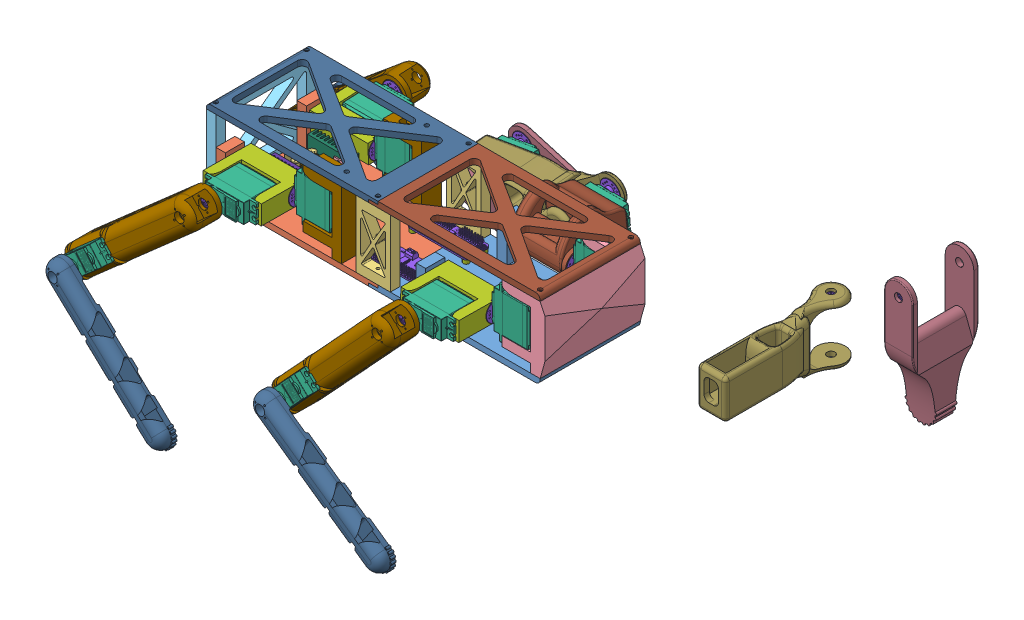
SolidWorks assembly RoboDogV3, configuration Standard. Lengths in mm.
Overall size (554.11 248.86 448.17).
97 component instances, 32 part files, 139 mates.
Components (placement in the parent):
- BottomPlate_Front-1: BottomPlate_Front [Standard] at (70.3304 -10.5488 180) size (180 46 105)
- BottomPlate_Back-1: BottomPlate_Back [Standard] at (-94.2849 -10.5488 185.4725) size (180 46 105)
- StructurePlate_MiddlePart-1: StructurePlate_MiddlePart [Standard] at (-22.5267 -4.5488 248) size (36 70 10)
- StructurePlate_MiddlePart-2: StructurePlate_MiddlePart [Standard] at (-22.5267 -4.5488 153) size (36 70 10)
- StructurePlate_Front-1: StructurePlate_Front [Standard] at (147.4733 -4.5488 258) x (0 0 -1) z (1 0 0) size (105.12 70 52.16)
- StructurePlate_Back-1: StructurePlate_Back [Standard] at (-182.5267 -4.5488 153) x (0 0 1) z (-1 0 0) size (105 70 10)
- mg996r-1: mg996r [Default] at (117.4733 34.4012 248.15) x (0 -1 0) z (0 0 -1) size (56.95 44.55 19.7)
- mg996r-2: mg996r [Default] at (117.4733 34.4012 162.85) x (0 -1 0) z (0 0 -1) size (56.95 44.55 19.7)
- ServoPart_ShoulderRight-1: ServoPart_ShoulderRight [Standard] at (40.4233 34.1896 237.0496) x (1 0 0) z (0 -0.999949 0.010096) size (73 50.02 20.04)
- mg996r-3: mg996r [Default] at (71.4733 24.8449 287.1465) x (-1 0 0) z (0 0.999949 -0.010096) size (56.95 44.55 19.7)
- attachmentCircular (1)-1: attachmentCircular (1) [Default] at (99.4233 24.3012 248.15) x (0 -1 0) z (0 0 1) size (20.7 5.75 20.7)
- Teil1^RoboDogV3-1: Teil1^RoboDogV3 [Standard] at origin (virtual)
- StructurePart_BackLegs-1: StructurePart_BackLegs [Standard] at (-50.9186 -4.5488 237) x (0 0 1) z (-1 0 0) size (21.05 70 40.02)
- mg996r-5: mg996r [Default] at (-90.9186 35.5012 246.85) x (0 -1 0) z (0 0 -1) size (56.95 44.55 19.7)
- mg996r-6: mg996r [Default] at (-136.9186 25.8546 285.8477) x (-1 0 0) z (0 0.99997 -0.00778) size (56.95 44.55 19.7)
- attachmentCircular (1)-3: attachmentCircular (1) [Default] at (-108.9686 25.4012 246.85) x (0 -1 0) z (0 0 1) size (20.7 5.75 20.7)
- ServoPart_ShoulderRight-3: ServoPart_ShoulderRight [Standard] at (-167.9686 35.3153 235.7725) x (1 0 0) z (0 -0.99997 0.00778) size (73 50.02 20.04)
- ServoPart_ShoulderRight-4: ServoPart_ShoulderRight [Standard] at (-167.9686 14.9087 173.3812) x (1 0 0) z (0 0.998954 0.045725) size (73 50.02 20.04)
- attachmentCircular (1)-4: attachmentCircular (1) [Default] at (-108.9686 25.4012 162.85) x (0 -1 0) z (0 0 1) size (20.7 5.75 20.7)
- mg996r-7: mg996r [Default] at (-136.9186 27.0346 123.8839) x (-1 0 0) z (0 -0.998954 -0.045725) size (56.95 44.55 19.7)
- mg996r-8: mg996r [Default] at (-90.9186 35.5012 162.85) x (0 -1 0) z (0 0 -1) size (56.95 44.55 19.7)
- StructurePart_BackLegs-2: StructurePart_BackLegs [Standard] at (-50.9186 -4.5488 153) x (0 0 1) z (-1 0 0) size (21.05 70 40.02)
- TopPlate_Back-1: TopPlate_Back [Standard] at (-105.3838 71.4512 180) x (-1 0 0) z (0 0 1) size (180 6 105)
- TopPlate_Front-1: TopPlate_Front [Standard] at (59.2315 71.4512 185.4725) x (-1 0 0) z (0 0 1) size (180 6 105)
- dcdc_converter.STEP-1: dcdc_converter.STEP [Standard] at (-133.5601 1.0512 205.6181) x (0.008727 0 -0.999962) z (0.999962 0 0.008727) size (53.6 27.7 60)
  - Bornera_terminal_7_62mm_2P.STEP-1: Bornera_terminal_7_62mm_2P.STEP [Standard] at (-0.13 0 17.5) x (-1 0 0) z (0 0 -1) size (16.14 14.75 12.1)
    - terminal-Base.STEP-1: terminal-Base.STEP [Standard] at origin size (16.14 12.5 12.1)
    - screw pad.STEP-1: screw pad.STEP [Standard] at (-3.8725 6.75 -5.95) size (6 9.75 10)
    - screw-term.STEP-1: screw-term.STEP [Standard] at (-3.8725 7.5 -5.95) x (-0.497999 0 -0.867177) z (0.867177 0 -0.497999) size (5 6.51 5)
    - screw pad.STEP-2: screw pad.STEP [Standard] at (3.8725 6.75 -5.95) size (6 9.75 10)
    - screw-term.STEP-2: screw-term.STEP [Standard] at (3.8725 7.5 -5.95) x (-0.426017 0 -0.904715) z (0.904715 0 -0.426017) size (5 6.51 5)
  - Bornera_terminal_7_62mm_2P.STEP-2: Bornera_terminal_7_62mm_2P.STEP [Standard] at (-7.13 0 -29.4) x (-1 0 0) z (0 0 -1) size (16.14 14.75 12.1)
    - terminal-Base.STEP-1: terminal-Base.STEP [Standard] at origin size (16.14 12.5 12.1)
    - screw pad.STEP-1: screw pad.STEP [Standard] at (-3.8725 6.75 -5.95) size (6 9.75 10)
    - screw-term.STEP-1: screw-term.STEP [Standard] at (-3.8725 7.5 -5.95) x (-0.497999 0 -0.867177) z (0.867177 0 -0.497999) size (5 6.51 5)
    - screw pad.STEP-2: screw pad.STEP [Standard] at (3.8725 6.75 -5.95) size (6 9.75 10)
    - screw-term.STEP-2: screw-term.STEP [Standard] at (3.8725 7.5 -5.95) x (-0.426017 0 -0.904715) z (0.904715 0 -0.426017) size (5 6.51 5)
  - heatsink 45x10x12r.STEP-1: heatsink 45x10x12r.STEP [Standard] at (16.8 0 0) size (10 25 45)
  - pcb.STEP-1: pcb.STEP [Standard] at origin size (45.5 1.61 60)
  - heatsink 45x10x12r-0.STEP-1: heatsink 45x10x12r-0.STEP [Standard] at (-16.8 0 0) x (-1 0 0) z (0 0 -1) size (10 25 45)
  - coil.STEP-1: coil.STEP [Standard] at (0 12.5 1) size (24 24 11)
  - Trimpot 3296W_Valor predeterminado.STEP-1: Trimpot 3296W_Valor predeterminado.STEP [Standard] at (9.485 0 -27.085) x (-1 0 0) z (0 1 0) size (9.53 4.83 14.15)
  - Trimpot 3296W_Valor predeterminado.STEP-2: Trimpot 3296W_Valor predeterminado.STEP [Standard] at (9.485 0 -21.755) x (-1 0 0) z (0 1 0) size (9.53 4.83 14.15)
  - c20x10x5.STEP-1: c20x10x5.STEP [Standard] at (5.27 0.525 11.8) x (0 0 -1) z (1 0 0) size (10.05 23.25 16.46)
  - c20x10x5.STEP-2: c20x10x5.STEP [Standard] at (-5.27 0.525 11.8) x (0 0 -1) z (1 0 0) size (10.05 23.25 16.46)
  - c20x8x4.STEP-1: c20x8x4.STEP [Standard] at (0 0.525 -9) x (0 0 -1) z (1 0 0) size (8.05 23.25 13.09)
  - c20x8x4.STEP-2: c20x8x4.STEP [Standard] at (-8.1 0.525 -9) x (0 0 -1) z (1 0 0) size (8.05 23.25 13.09)
  - c20x8x4.STEP-3: c20x8x4.STEP [Standard] at (8.1 0.525 -9) x (0 0 -1) z (1 0 0) size (8.05 23.25 13.09)
  - MOSFET.STEP-1: MOSFET.STEP [Standard] at (-16.8 9.3003 11.65) x (0 0 -1) z (1 0 0) size (10.16 22.6 4.45)
  - MOSFET.STEP-2: MOSFET.STEP [Standard] at (16.8 9.3003 11.65) x (0 0 1) z (-1 0 0) size (10.16 22.6 4.45)
  - 3mm LED.STEP-1: 3mm LED.STEP [Standard] at (-12.05 5 22.2) x (-1 0 0) z (0 0 -1) size (3.4 10.4 3.8)
  - Selector Switch - SS12D00.STEP-1: Selector Switch - SS12D00.STEP [Standard] at (14.1989 2.1071 23.2) x (0 0 -1) z (1 0 0) size (8.59 9.5 3.71)
- DistancingRing-1: DistancingRing [Standard] at (-105.3067 -0.5488 218.5) x (-0.837169 0 -0.546944) z (-0.546944 0 0.837169) size (6 4 6)
- DistancingRing-2: DistancingRing [Standard] at (-105.3021 -0.5488 192.5) x (-0.837169 0 -0.546944) z (-0.546944 0 0.837169) size (6 4 6)
- DistancingRing-3: DistancingRing [Standard] at (-163.3021 -4.5488 192.5) size (6 4 6)
- DistancingRing-4: DistancingRing [Standard] at (-163.3067 -0.5488 218.5) x (-0.837169 0 -0.546944) z (-0.546944 0 0.837169) size (6 4 6)
- DistancingRing-5: DistancingRing [Standard] at (116.3693 -0.5488 229.0306) x (-0.837169 0 -0.546944) z (-0.546944 0 0.837169) size (6 4 6)
- DistancingRing-6: DistancingRing [Standard] at (116.3693 -0.5488 180.0306) x (-0.837169 0 -0.546944) z (-0.546944 0 0.837169) size (6 4 6)
- DistancingRing-7: DistancingRing [Standard] at (58.3693 -0.5488 180.0306) x (-0.837169 0 -0.546944) z (-0.546944 0 0.837169) size (6 4 6)
- DistancingRing-8: DistancingRing [Standard] at (58.3693 -0.5488 229.0306) x (-0.837169 0 -0.546944) z (-0.546944 0 0.837169) size (6 4 6)
- 12Channel PWM-1: 12Channel PWM [Default] at (-15.1746 -0.5488 181.423) x (0.00022 0 1) z (-1 0 0.00022) size (25.4 7.55 66.7)
- 12Channel PWM-2: 12Channel PWM [Default] at (-15.1726 -0.5488 229.57) x (0 0 -1) z (1 0 0) size (25.4 7.55 66.7)
- DistancingRing-9: DistancingRing [Standard] at (-43.1267 -4.5488 172.0292) size (6 4 6)
- DistancingRing-10: DistancingRing [Standard] at (-43.1226 -4.5488 190.8284) size (6 4 6)
- DistancingRing-11: DistancingRing [Standard] at (-43.1226 -4.5488 238.97) size (6 4 6)
- DistancingRing-12: DistancingRing [Standard] at (-43.1226 -4.5488 220.17) size (6 4 6)
- DistancingRing-13: DistancingRing [Standard] at (12.7774 -4.5488 190.8169) size (6 4 6)
- DistancingRing-14: DistancingRing [Standard] at (12.7733 -4.5488 172.0169) size (6 4 6)
- DistancingRing-15: DistancingRing [Standard] at (12.7774 -4.5488 238.97) size (6 4 6)
- DistancingRing-16: DistancingRing [Standard] at (12.7774 -4.5488 220.17) size (6 4 6)
- Leg_UpperPart-1: Leg_UpperPart [Standard] at (-273.3611 -65.0539 302.6054) x (-0.751239 -0.66001 0.005135) z (-0.66003 0.751217 -0.005844) size (170 30.18 30.18)
- attachmentCircular (1)-5: attachmentCircular (1) [Default] at (-147.0186 25.995 303.8971) x (0.751239 0.66001 -0.005135) z (-0.66003 0.751217 -0.005844) size (20.7 5.75 20.7)
- attachmentCircular (1)-6: attachmentCircular (1) [Default] at (61.3733 25.0271 305.1956) x (0.677926 0.735093 -0.007422) z (-0.73513 0.677891 -0.006844) size (20.7 5.75 20.7)
- Leg_UpperPart-2: Leg_UpperPart [Standard] at (-54.7322 -78.764 304.2434) x (-0.677926 -0.735093 0.007422) z (-0.73513 0.677891 -0.006844) size (170 30.18 30.18)
- attachmentCircular (1)-8: attachmentCircular (1) [Default] at (-147.0186 27.86 105.8528) x (0.766628 0.64142 0.02936) z (0.642092 -0.765826 -0.035054) size (20.7 5.75 20.7)
- Leg_UpperPart-4: Leg_UpperPart [Standard] at (-256.2145 -83.139 102.7741) x (-0.766628 -0.64142 -0.02936) z (0.642092 -0.765826 -0.035054) size (170 30.18 30.18)
- mg996r-9: mg996r [Default] at (-22.3983 -66.0422 334.1165) x (-0.677926 -0.735093 0.007422) z (-0.73513 0.677891 -0.006844) size (56.95 44.55 19.7)
- mg996r-10: mg996r [Default] at (-240.73 -56.5843 332.5404) x (-0.751239 -0.66001 0.005135) z (-0.66003 0.751217 -0.005844) size (56.95 44.55 19.7)
- mg996r-11: mg996r [Default] at (-243.6238 -50.1886 74.251) x (-0.766628 -0.64142 -0.02936) z (0.642092 -0.765826 -0.035054) size (56.95 44.55 19.7)
- Leg Bottom-1: Leg Bottom [Standard] at (-237.8462 -89.7658 348.849) x (0.735504 -0.6775 0.005271) z (0 0.00778 0.99997) size (166.25 27.5 15)
- attachmentCircular (1)-9: attachmentCircular (1) [Default] at (-248.3176 -63.11 350.6417) x (0.735504 -0.6775 0.005271) z (0.677521 0.735481 -0.005722) size (20.7 5.75 20.7)
- attachmentCircular (1)-10: attachmentCircular (1) [Default] at (-29.2454 -73.2844 352.2405) x (0.822234 -0.569121 0.005746) z (0.56915 0.822192 -0.008301) size (20.7 5.75 20.7)
- Leg Bottom-2: Leg Bottom [Standard] at (-15.186 -98.2377 350.4923) x (0.822234 -0.569121 0.005746) z (0 0.010096 0.999949) size (166.25 27.5 15)
- attachmentCircular (1)-12: attachmentCircular (1) [Default] at (-251.3668 -55.8416 55.9233) x (0.787176 -0.616083 -0.0282) z (-0.616728 -0.786353 -0.035994) size (20.7 5.75 20.7)
- Leg Bottom-4: Leg Bottom [Standard] at (-223.3866 -61.9687 57.645) x (0.787176 -0.616083 -0.0282) z (0 0.045725 -0.998954) size (166.25 27.5 15)
- attachmentCircular (1)-13: attachmentCircular (1) [Default] at (98.4233 24.3012 162.85) x (0 -0.080731 0.996736) z (0 0.996736 0.080731) size (20.7 5.75 20.7)
- Shoulder-1: Shoulder [Standard] at (37.9233 24.3012 162.85) x (0 0.089032 -0.996029) z (1 0 0) size (78.66 54.3 75)
- mg996r-13: mg996r [Default] at (68.8733 29.0925 104.545) x (-1 0 0) z (0 -0.996029 -0.089032) size (56.95 44.55 19.7)
- mg996r-14: mg996r [Default] at (-38.5219 12.4325 88.498) x (-0.983751 -0.178826 -0.015985) z (0.179539 -0.979844 -0.087585) size (56.95 44.55 19.7)
- LegTop-1: LegTop [Standard] at (30.1585 15.8904 136.4965) x (0 -0.089032 0.996029) z (-0.983751 -0.178826 -0.015985) size (63.28 30 140.57)
- attachmentCircular (1)-14: attachmentCircular (1) [Default] at (58.7733 30.9621 83.6284) x (0.698629 -0.712642 -0.063701) z (-0.715484 -0.695855 -0.0622) size (20.7 5.75 20.7)
- LegBottom-1: LegBottom [Standard] at (74.9502 -12.136 63.2102) x (-0.313233 -0.945905 -0.084551) z (0 0.089032 -0.996029) size (33 141.27 69)
- attachmentCircular (1)-15: attachmentCircular (1) [Default] at (-48.4578 12.407 68.416) x (0.903765 0.426329 0.038108) z (0.428029 -0.900176 -0.080464) size (20.7 5.75 20.7)
- LegBottom-2: LegBottom [Standard] at (247.1201 -139.1368 -12.9277) size (33 141.27 69)
- LegTop-3: LegTop [Standard] at (154.911 -132.4306 -14.4716) x (0 -1 0) z (0 0 1) size (63.28 30 140.57)
- attachmentCircular (1)-16: attachmentCircular (1) [Default] at (262.1201 -14.1368 -15.9277) x (-0.923728 -0.383049 0) z (0.383049 -0.923728 0) size (20.7 5.75 20.7)
- attachmentCircular (1)-17: attachmentCircular (1) [Default] at (159.911 -78.4306 -44.4716) x (-0.837169 0 -0.546944) z (-0.546944 0 0.837169) size (20.7 5.75 20.7)
Mates (geometry in assembly coordinates):
- Deckungsgleich1: coincident anti-aligned: line of BottomPlate_Front-1 through (-22.5267 -7.5488 153) axis (0 0 1); line of BottomPlate_Back-1 through (-22.5267 -7.5488 258) axis (0 0 -1)
- Deckungsgleich2: coincident anti-aligned: line of BottomPlate_Front-1 through (-22.5267 -7.5488 258) axis (1 0 0); line of BottomPlate_Back-1 through (-12.5267 -7.5488 258) axis (-1 0 0)
- Konzentrisch1: concentric aligned: circle of BottomPlate_Back-1; circle of StructurePlate_MiddlePart-1
- Deckungsgleich3: coincident aligned: line of BottomPlate_Back-1 through (-192.5267 -4.5488 258) axis (1 0 0); line of StructurePlate_MiddlePart-1 through (-35.6225 -4.5488 258) axis (1 0 0)
- Konzentrisch2: concentric aligned: circle of BottomPlate_Back-1; circle of StructurePlate_MiddlePart-2
- Deckungsgleich4: coincident anti-aligned: line of BottomPlate_Back-1 through (-12.5267 -4.5488 153) axis (-1 0 0); line of StructurePlate_MiddlePart-2 through (-35.6225 -4.5488 153) axis (1 0 0)
- Deckungsgleich5: coincident aligned: line of BottomPlate_Front-1 through (157.4733 -4.5488 258) axis (0 0 -1); line of StructurePlate_Front-1 through (157.4733 -4.5488 258) axis (0 0 -1)
- Konzentrisch5: concentric anti-aligned: circle of BottomPlate_Back-1; circle of StructurePlate_Back-1
- Konzentrisch6: concentric anti-aligned: circle of BottomPlate_Back-1; circle of StructurePlate_Back-1
- Deckungsgleich6: coincident aligned: line of BottomPlate_Back-1 through (-192.5267 -4.5488 153) axis (0 0 1); line of StructurePlate_Back-1 through (-192.5267 -4.5488 153) axis (0 0 1)
- Konzentrisch8: concentric anti-aligned: circle of BottomPlate_Front-1; circle of StructurePlate_Front-1
- Deckungsgleich16: coincident anti-aligned: plane of StructurePlate_Front-1 through (157.4733 14.4512 258) normal (0 1 0); plane of mg996r-1 through (138.7733 14.4512 257.3) normal (0 -1 0)
- Deckungsgleich18: coincident anti-aligned: plane of StructurePlate_Front-1 through (117.4733 -4.5488 258) normal (-1 0 0); plane of mg996r-1 through (117.4733 61.1617 254.675) normal (1 0 0)
- Deckungsgleich19: coincident aligned: plane of StructurePlate_Front-1 through (157.4733 -4.5488 258) normal (0 0 1); plane of mg996r-1 through (138.7733 53.6512 258) normal (0 0 1)
- Deckungsgleich20: coincident anti-aligned: plane of StructurePlate_Front-1 through (117.4733 -4.5488 258) normal (-1 0 0); plane of mg996r-2 through (117.4733 61.1617 169.375) normal (1 0 0)
- Deckungsgleich21: coincident anti-aligned: plane of StructurePlate_Front-1 through (157.4733 14.4512 153) normal (0 1 0); plane of mg996r-2 through (138.7733 14.4512 172) normal (0 -1 0)
- Deckungsgleich22: coincident aligned: plane of StructurePlate_Front-1 through (157.4733 -4.5488 153) normal (0 0 -1); plane of mg996r-2 through (138.7733 15.1512 153) normal (0 0 -1)
- Deckungsgleich25: coincident anti-aligned: plane of ServoPart_ShoulderRight-1 through (40.4233 14.6954 287.249) normal (0 0.010096 0.999949); plane of mg996r-3 through (98.2338 18.3203 287.2124) normal (0 -0.010096 -0.999949)
- Deckungsgleich28: coincident anti-aligned: plane of ServoPart_ShoulderRight-1 through (91.4233 34.3915 257.0486) normal (-1 0 0); plane of mg996r-3 through (91.4233 33.7794 265.7552) normal (1 0 0)
- Deckungsgleich29: coincident aligned: plane of ServoPart_ShoulderRight-1 through (40.4233 34.1896 237.0496) normal (0 0.999949 -0.010096); plane of mg996r-3 through (52.2233 34.4794 265.7481) normal (0 0.999949 -0.010096)
- Deckungsgleich31: coincident anti-aligned: plane of ServoPart_ShoulderRight-1 through (99.4233 24.3012 248.15) normal (1 0 0); plane of attachmentCircular (1)-1 through (99.4233 24.3012 248.15) normal (-1 0 0)
- Konzentrisch9: concentric aligned: circle of ServoPart_ShoulderRight-1; circle of attachmentCircular (1)-1
- Konzentrisch10: concentric anti-aligned: circle of mg996r-1; circle of attachmentCircular (1)-1
- Deckungsgleich32: coincident anti-aligned: plane of mg996r-1 through (105.1733 24.3012 248.15) normal (-1 0 0); plane of attachmentCircular (1)-1 through (105.1733 24.3012 248.15) normal (1 0 0)
- Deckungsgleich39: coincident aligned: plane of StructurePart_BackLegs-1 through (-50.9186 -4.5488 237) normal (0 0 -1); plane of mg996r-5 through (-69.6186 16.2512 237) normal (0 0 -1)
- Deckungsgleich40: coincident anti-aligned: plane of StructurePart_BackLegs-1 through (-60.9186 55.4512 258) normal (0 -1 0); plane of mg996r-5 through (-69.6186 55.4512 237.7) normal (0 1 0)
- Deckungsgleich41: coincident anti-aligned: plane of BottomPlate_Back-1 through (-94.2849 -4.5488 185.4725) normal (0 1 0); plane of StructurePart_BackLegs-1 through (-50.9186 -4.5488 258) normal (0 -1 0)
- Deckungsgleich42: coincident anti-aligned: plane of StructurePart_BackLegs-1 through (-90.9186 65.4512 258) normal (-1 0 0); plane of mg996r-5 through (-90.9186 62.2617 253.375) normal (1 0 0)
- Deckungsgleich43: coincident aligned: plane of BottomPlate_Back-1 through (-192.5267 -4.5488 258) normal (0 0 1); plane of StructurePart_BackLegs-1 through (-50.9186 -4.5488 258) normal (0 0 1)
- Konzentrisch14: concentric aligned: circle of attachmentCircular (1)-3; circle of ServoPart_ShoulderRight-3
- Deckungsgleich44: coincident aligned: plane of mg996r-6 through (-156.1686 35.5386 264.4717) normal (0 0.99997 -0.00778); plane of ServoPart_ShoulderRight-3 through (-167.9686 35.3153 235.7725) normal (0 0.99997 -0.00778)
- Deckungsgleich45: coincident anti-aligned: plane of mg996r-6 through (-110.158 19.3298 285.8984) normal (0 -0.00778 -0.99997); plane of ServoPart_ShoulderRight-3 through (-167.9686 15.7049 285.9266) normal (0 0.00778 0.99997)
- Deckungsgleich46: coincident anti-aligned: plane of attachmentCircular (1)-3 through (-108.9686 25.4012 246.85) normal (-1 0 0); plane of ServoPart_ShoulderRight-3 through (-108.9686 25.4012 246.85) normal (1 0 0)
- Deckungsgleich47: coincident anti-aligned: plane of mg996r-6 through (-116.9686 34.8386 264.4771) normal (1 0 0); plane of ServoPart_ShoulderRight-3 through (-116.9686 35.4709 255.7719) normal (-1 0 0)
- Konzentrisch15: concentric anti-aligned: circle of mg996r-5; circle of attachmentCircular (1)-3
- Deckungsgleich48: coincident anti-aligned: plane of mg996r-5 through (-103.2186 25.4012 246.85) normal (-1 0 0); plane of attachmentCircular (1)-3 through (-103.2186 25.4012 246.85) normal (1 0 0)
- Deckungsgleich49: coincident anti-aligned: plane of mg996r-8 through (-69.6186 55.4512 153.7) normal (0 1 0); plane of StructurePart_BackLegs-2 through (-60.9186 55.4512 174) normal (0 -1 0)
- Deckungsgleich50: coincident aligned: plane of mg996r-8 through (-69.6186 16.2512 153) normal (0 0 -1); plane of StructurePart_BackLegs-2 through (-50.9186 -4.5488 153) normal (0 0 -1)
- Deckungsgleich51: coincident anti-aligned: plane of attachmentCircular (1)-4 through (-103.2186 25.4012 162.85) normal (1 0 0); plane of mg996r-8 through (-103.2186 25.4012 162.85) normal (-1 0 0)
- Konzentrisch16: concentric aligned: circle of ServoPart_ShoulderRight-4; circle of attachmentCircular (1)-4
- Konzentrisch17: concentric anti-aligned: circle of attachmentCircular (1)-4; circle of mg996r-8
- Deckungsgleich52: coincident aligned: plane of ServoPart_ShoulderRight-4 through (-167.9686 14.9087 173.3812) normal (0 -0.998954 -0.045725); plane of mg996r-7 through (-156.1686 16.221 144.7113) normal (0 -0.998954 -0.045725)
- Deckungsgleich53: coincident anti-aligned: plane of ServoPart_ShoulderRight-4 through (-116.9686 15.8232 153.4022) normal (-1 0 0); plane of mg996r-7 through (-116.9686 16.9203 144.7433) normal (1 0 0)
- Deckungsgleich54: coincident anti-aligned: plane of mg996r-8 through (-90.9186 62.2617 169.375) normal (1 0 0); plane of StructurePart_BackLegs-2 through (-90.9186 65.4512 174) normal (-1 0 0)
- Deckungsgleich55: coincident anti-aligned: plane of ServoPart_ShoulderRight-4 through (-167.9686 37.174 124.348) normal (0 0.045725 -0.998954); plane of mg996r-7 through (-110.158 33.5528 124.1823) normal (0 -0.045725 0.998954)
- Deckungsgleich56: coincident anti-aligned: plane of ServoPart_ShoulderRight-4 through (-108.9686 25.4012 162.85) normal (1 0 0); plane of attachmentCircular (1)-4 through (-108.9686 25.4012 162.85) normal (-1 0 0)
- Deckungsgleich57: coincident anti-aligned: plane of BottomPlate_Back-1 through (-94.2849 -4.5488 185.4725) normal (0 1 0); plane of StructurePart_BackLegs-2 through (-50.9186 -4.5488 174) normal (0 -1 0)
- Deckungsgleich58: coincident aligned: plane of BottomPlate_Back-1 through (-192.5267 -4.5488 153) normal (0 0 -1); plane of StructurePart_BackLegs-2 through (-50.9186 -4.5488 153) normal (0 0 -1)
- Konzentrisch18: concentric aligned: circle of BottomPlate_Back-1; circle of StructurePart_BackLegs-1
- Konzentrisch19: concentric aligned: cylinder of BottomPlate_Back-1 through (-55.9186 -4.5488 163.5) axis (0 -1 0) radius 1.5; circle of StructurePart_BackLegs-2
- Konzentrisch20: concentric anti-aligned: circle of StructurePlate_Front-1; circle of TopPlate_Front-1
- Deckungsgleich59: coincident aligned: line of StructurePlate_Front-1 through (157.4733 65.4512 153) axis (0 0 1); line of TopPlate_Front-1 through (157.4733 65.4512 153) axis (0 0 1)
- Deckungsgleich60: coincident anti-aligned: circle of TopPlate_Back-1; circle of TopPlate_Front-1
- Deckungsgleich61: coincident anti-aligned: line of TopPlate_Back-1 through (-12.5267 68.4512 153) axis (0 0 1); line of TopPlate_Front-1 through (-12.5267 68.4512 258) axis (0 0 -1)
- Deckungsgleich63: coincident aligned: circle of BottomPlate_Back-1; circle of DistancingRing-3
- Deckungsgleich64: coincident anti-aligned: circle of BottomPlate_Back-1; circle of DistancingRing-4
- Deckungsgleich65: coincident anti-aligned: circle of BottomPlate_Back-1; circle of DistancingRing-1
- Deckungsgleich66: coincident anti-aligned: circle of BottomPlate_Back-1; circle of DistancingRing-2
- Deckungsgleich67: coincident anti-aligned: circle of BottomPlate_Front-1; circle of DistancingRing-6
- Deckungsgleich68: coincident anti-aligned: circle of BottomPlate_Front-1; circle of DistancingRing-7
- Deckungsgleich69: coincident anti-aligned: circle of BottomPlate_Front-1; circle of DistancingRing-5
- Deckungsgleich70: coincident anti-aligned: circle of BottomPlate_Front-1; circle of DistancingRing-8
- Deckungsgleich71: coincident anti-aligned: plane of dcdc_converter.STEP-1/pcb.STEP-1 through (-133.5601 -0.5488 205.6181) normal (0 -1 0); plane of DistancingRing-4 through (-163.3067 -0.5488 218.5) normal (0 1 0)
- Deckungsgleich72: coincident aligned: circle of BottomPlate_Back-1; circle of DistancingRing-9
- Deckungsgleich73: coincident aligned: circle of BottomPlate_Back-1; circle of DistancingRing-10
- Deckungsgleich74: coincident aligned: circle of BottomPlate_Back-1; circle of DistancingRing-12
- Deckungsgleich75: coincident aligned: circle of BottomPlate_Back-1; circle of DistancingRing-11
- Konzentrisch21: concentric aligned: circle of 12Channel PWM-1; circle of DistancingRing-9
- Konzentrisch22: concentric aligned: circle of 12Channel PWM-1; circle of DistancingRing-10
- Deckungsgleich76: coincident anti-aligned: plane of 12Channel PWM-1 through (12.7774 -0.5488 190.8169) normal (0 -1 0); plane of DistancingRing-9 through (-43.1267 -0.5488 172.0292) normal (0 1 0)
- Konzentrisch23: concentric aligned: circle of 12Channel PWM-2; circle of DistancingRing-11
- Konzentrisch24: concentric aligned: circle of 12Channel PWM-2; circle of DistancingRing-12
- Deckungsgleich77: coincident anti-aligned: plane of 12Channel PWM-2 through (-43.1226 -0.5488 220.17) normal (0 -1 0); plane of DistancingRing-12 through (-43.1226 -0.5488 220.17) normal (0 1 0)
- Deckungsgleich78: coincident aligned: circle of BottomPlate_Front-1; circle of DistancingRing-14
- Deckungsgleich79: coincident aligned: circle of BottomPlate_Front-1; circle of DistancingRing-13
- Deckungsgleich80: coincident aligned: circle of BottomPlate_Front-1; circle of DistancingRing-16
- Deckungsgleich81: coincident aligned: circle of BottomPlate_Front-1; circle of DistancingRing-15
- Konzentrisch25: concentric aligned: circle of Leg_UpperPart-1; circle of attachmentCircular (1)-5
- Konzentrisch26: concentric aligned: circle of Leg_UpperPart-1; circle of attachmentCircular (1)-5
- Deckungsgleich82: coincident anti-aligned: plane of Leg_UpperPart-1 through (-147.0186 25.995 303.8971) normal (0 -0.00778 -0.99997); plane of attachmentCircular (1)-5 through (-147.0186 25.995 303.8971) normal (0 0.00778 0.99997)
- Konzentrisch27: concentric aligned: circle of attachmentCircular (1)-6; circle of Leg_UpperPart-2
- Konzentrisch28: concentric aligned: circle of attachmentCircular (1)-6; circle of Leg_UpperPart-2
- Deckungsgleich83: coincident anti-aligned: plane of attachmentCircular (1)-6 through (61.3733 25.0271 305.1956) normal (0 0.010096 0.999949); plane of Leg_UpperPart-2 through (61.3733 25.0271 305.1956) normal (0 -0.010096 -0.999949)
- Konzentrisch31: concentric aligned: circle of attachmentCircular (1)-8; circle of Leg_UpperPart-4
- Konzentrisch32: concentric aligned: circle of attachmentCircular (1)-8; circle of Leg_UpperPart-4
- Deckungsgleich85: coincident anti-aligned: plane of attachmentCircular (1)-8 through (-147.0186 27.86 105.8528) normal (0 0.045725 -0.998954); plane of Leg_UpperPart-4 through (-147.0186 27.86 105.8528) normal (0 -0.045725 0.998954)
- Konzentrisch33: concentric anti-aligned: circle of mg996r-3; circle of attachmentCircular (1)-6
- Deckungsgleich86: coincident anti-aligned: plane of mg996r-3 through (61.3733 24.9691 299.4459) normal (0 0.010096 0.999949); plane of attachmentCircular (1)-6 through (61.3733 24.9691 299.4459) normal (0 -0.010096 -0.999949)
- Konzentrisch34: concentric anti-aligned: circle of mg996r-6; circle of attachmentCircular (1)-5
- Deckungsgleich87: coincident anti-aligned: plane of mg996r-6 through (-147.0186 25.9503 298.1473) normal (0 0.00778 0.99997); plane of attachmentCircular (1)-5 through (-147.0186 25.9503 298.1473) normal (0 -0.00778 -0.99997)
- Konzentrisch35: concentric anti-aligned: circle of mg996r-7; circle of attachmentCircular (1)-8
- Deckungsgleich88: coincident anti-aligned: plane of mg996r-7 through (-147.0186 27.597 111.5968) normal (0 0.045725 -0.998954); plane of attachmentCircular (1)-8 through (-147.0186 27.597 111.5968) normal (0 -0.045725 0.998954)
- Deckungsgleich90: coincident anti-aligned: plane of Leg_UpperPart-2 through (61.3733 25.3098 333.1942) normal (0 0.010096 0.999949); plane of mg996r-9 through (0.5401 -50.7939 333.9625) normal (0 -0.010096 -0.999949)
- Deckungsgleich91: coincident anti-aligned: plane of Leg_UpperPart-2 through (-1.5959 -58.5627 287.0386) normal (-0.677926 -0.735093 0.007422); plane of mg996r-9 through (-15.6001 -45.3894 312.6069) normal (0.677926 0.735093 -0.007422)
- Abstand1: distance = 0.75 mm anti-aligned: plane of Leg_UpperPart-2 through (-44.461 -74.8047 287.2025) normal (0.73513 -0.677891 0.006844); plane of mg996r-9 through (-42.6894 -73.7305 312.893) normal (-0.73513 0.677891 -0.006844)
- Abstand2: distance = 0.75 mm anti-aligned: plane of mg996r-10 through (-261.6927 -62.0558 311.2823) normal (-0.66003 0.751217 -0.005844); plane of Leg_UpperPart-1 through (-262.7136 -62.1543 285.5823) normal (0.66003 -0.751217 0.005844)
- Deckungsgleich94: coincident anti-aligned: plane of Leg_UpperPart-1 through (-147.0186 26.2128 331.8963) normal (0 0.00778 0.99997); plane of mg996r-10 through (-216.3198 -43.8238 332.4411) normal (0 -0.00778 -0.99997)
- Deckungsgleich95: coincident anti-aligned: plane of Leg_UpperPart-1 through (-249.183 -77.5542 285.7021) normal (0.751239 0.66001 -0.005135); plane of mg996r-10 through (-249.678 -76.7909 311.397) normal (-0.751239 -0.66001 0.005135)
- Deckungsgleich96: coincident anti-aligned: plane of Leg_UpperPart-4 through (-147.0186 29.1403 77.8821) normal (0 0.045725 -0.998954); plane of mg996r-11 through (-227.2981 -28.0268 75.2654) normal (0 -0.045725 0.998954)
- Deckungsgleich99: coincident anti-aligned: plane of Leg_UpperPart-4 through (-264.7611 -58.165 120.9351) normal (0.766628 0.64142 0.02936); plane of mg996r-11 through (-264.7932 -56.9516 95.2637) normal (-0.766628 -0.64142 -0.02936)
- Abstand4: distance = 0.75 mm anti-aligned: plane of mg996r-11 through (-235.1908 -31.2718 96.4392) normal (-0.642092 0.765826 0.035054); plane of Leg_UpperPart-4 through (-264.7611 -58.165 120.9351) normal (0.642092 -0.765826 -0.035054)
- Konzentrisch37: concentric aligned: circle of Leg Bottom-1; circle of attachmentCircular (1)-9
- Deckungsgleich103: coincident aligned: circle of Leg Bottom-1; circle of attachmentCircular (1)-9
- Deckungsgleich104: coincident anti-aligned: plane of Leg Bottom-1 through (-248.3176 -63.11 350.6417) normal (0 -0.00778 -0.99997); plane of attachmentCircular (1)-9 through (-248.3176 -63.11 350.6417) normal (0 0.00778 0.99997)
- Konzentrisch38: concentric aligned: circle of attachmentCircular (1)-10; circle of Leg Bottom-2
- Deckungsgleich105: coincident aligned: circle of attachmentCircular (1)-10; circle of Leg Bottom-2
- Konzentrisch40: concentric aligned: circle of attachmentCircular (1)-12; circle of Leg Bottom-4
- Deckungsgleich109: coincident aligned: circle of attachmentCircular (1)-12; circle of Leg Bottom-4
- Deckungsgleich110: coincident anti-aligned: plane of attachmentCircular (1)-12 through (-251.3668 -55.8416 55.9233) normal (0 0.045725 -0.998954); plane of Leg Bottom-4 through (-251.3668 -55.8416 55.9233) normal (0 -0.045725 0.998954)
- Konzentrisch41: concentric anti-aligned: circle of mg996r-9; circle of attachmentCircular (1)-10
- Deckungsgleich111: coincident anti-aligned: plane of mg996r-9 through (-29.2454 -73.3424 346.4908) normal (0 0.010096 0.999949); plane of attachmentCircular (1)-10 through (-29.2454 -73.3424 346.4908) normal (0 -0.010096 -0.999949)
- Konzentrisch42: concentric anti-aligned: circle of mg996r-10; circle of attachmentCircular (1)-9
- Deckungsgleich112: coincident anti-aligned: plane of mg996r-10 through (-248.3176 -63.1548 344.8919) normal (0 0.00778 0.99997); plane of attachmentCircular (1)-9 through (-248.3176 -63.1548 344.8919) normal (0 -0.00778 -0.99997)
- Konzentrisch43: concentric anti-aligned: circle of mg996r-11; circle of attachmentCircular (1)-12
- Deckungsgleich113: coincident anti-aligned: plane of mg996r-11 through (-251.3668 -56.1045 61.6673) normal (0 0.045725 -0.998954); plane of attachmentCircular (1)-12 through (-251.3668 -56.1045 61.6673) normal (0 -0.045725 0.998954)
- Konzentrisch45: concentric aligned: circle of attachmentCircular (1)-10; circle of Leg Bottom-2
- Konzentrisch46: concentric aligned: circle of attachmentCircular (1)-13; circle of Shoulder-1
- Deckungsgleich115: coincident anti-aligned: plane of attachmentCircular (1)-13 through (98.4233 24.3012 162.85) normal (-1 0 0); plane of Shoulder-1 through (98.4233 24.3012 162.85) normal (1 0 0)
- Konzentrisch47: concentric aligned: circle of attachmentCircular (1)-13; circle of Shoulder-1
- Konzentrisch48: concentric anti-aligned: circle of mg996r-2; circle of attachmentCircular (1)-13
- Abstand5: distance = 1 mm anti-aligned: plane of attachmentCircular (1)-13 through (104.1733 24.3012 162.85) normal (1 0 0); plane of mg996r-2 through (105.1733 24.3012 162.85) normal (-1 0 0)
- Deckungsgleich122: coincident anti-aligned: plane of Shoulder-1 through (42.4233 35.9653 138.2909) normal (0 -0.996029 -0.089032); plane of mg996r-13 through (88.1233 37.007 126.6374) normal (0 0.996029 0.089032)
- Deckungsgleich123: coincident anti-aligned: plane of Shoulder-1 through (48.9233 18.9828 103.6414) normal (1 0 0); plane of mg996r-13 through (48.9233 36.3098 126.5751) normal (-1 0 0)
- Deckungsgleich124: coincident anti-aligned: plane of Shoulder-1 through (42.4233 18.9828 103.6414) normal (0 0.089032 -0.996029); plane of mg996r-13 through (95.6338 35.5916 105.126) normal (0 -0.089032 0.996029)
- Deckungsgleich125: coincident anti-aligned: plane of Shoulder-1 through (42.4233 16.0447 136.5103) normal (0 -0.089032 0.996029); plane of LegTop-1 through (28.3631 25.6889 137.3724) normal (0 0.089032 -0.996029)
- Deckungsgleich126: coincident anti-aligned: plane of mg996r-14 through (-17.2533 5.1381 109.2309) normal (0.983751 0.178826 0.015985); plane of LegTop-1 through (-20.6645 22.9806 119.5605) normal (-0.983751 -0.178826 -0.015985)
- Deckungsgleich127: coincident anti-aligned: plane of mg996r-14 through (-21.3532 23.63 110.8839) normal (-0.179539 0.979844 0.087585); plane of LegTop-1 through (-60.9983 15.6488 118.9051) normal (0.179539 -0.979844 -0.087585)
- Deckungsgleich129: coincident anti-aligned: plane of mg996r-14 through (-13.3677 23.6115 89.4973) normal (0 -0.089032 0.996029); plane of LegTop-1 through (27.0351 9.4269 88.2294) normal (0 0.089032 -0.996029)
- Deckungsgleich130: coincident anti-aligned: plane of LegTop-1 through (58.7733 30.9621 83.6284) normal (0 -0.089032 0.996029); plane of attachmentCircular (1)-14 through (58.7733 30.9621 83.6284) normal (0 0.089032 -0.996029)
- Konzentrisch49: concentric aligned: circle of LegTop-1; circle of attachmentCircular (1)-14
- Konzentrisch50: concentric anti-aligned: circle of Shoulder-1; circle of LegTop-1
- Deckungsgleich131: coincident anti-aligned: plane of LegBottom-1 through (-48.4578 12.407 68.416) normal (0 -0.089032 0.996029); plane of attachmentCircular (1)-15 through (-48.4578 12.407 68.416) normal (0 0.089032 -0.996029)
- Konzentrisch51: concentric aligned: circle of LegBottom-1; circle of attachmentCircular (1)-15
- Konzentrisch52: concentric aligned: circle of LegTop-1; circle of LegBottom-1
- Deckungsgleich132: coincident anti-aligned: plane of LegTop-1 through (27.0351 5.7766 129.0666) normal (0 -0.089032 0.996029); plane of LegBottom-1 through (-67.4014 -2.5327 128.3238) normal (0 0.089032 -0.996029)
- Konzentrisch55: concentric aligned: circle of LegBottom-2; circle of attachmentCircular (1)-16
- Deckungsgleich133: coincident anti-aligned: plane of LegBottom-2 through (262.1201 -14.1368 -15.9277) normal (0 0 -1); plane of attachmentCircular (1)-16 through (262.1201 -14.1368 -15.9277) normal (0 0 1)
- Konzentrisch56: concentric aligned: circle of LegTop-3; circle of attachmentCircular (1)-17
- Deckungsgleich134: coincident anti-aligned: plane of LegTop-3 through (159.911 -78.4306 -44.4716) normal (0 -1 0); plane of attachmentCircular (1)-17 through (159.911 -78.4306 -44.4716) normal (0 1 0)
